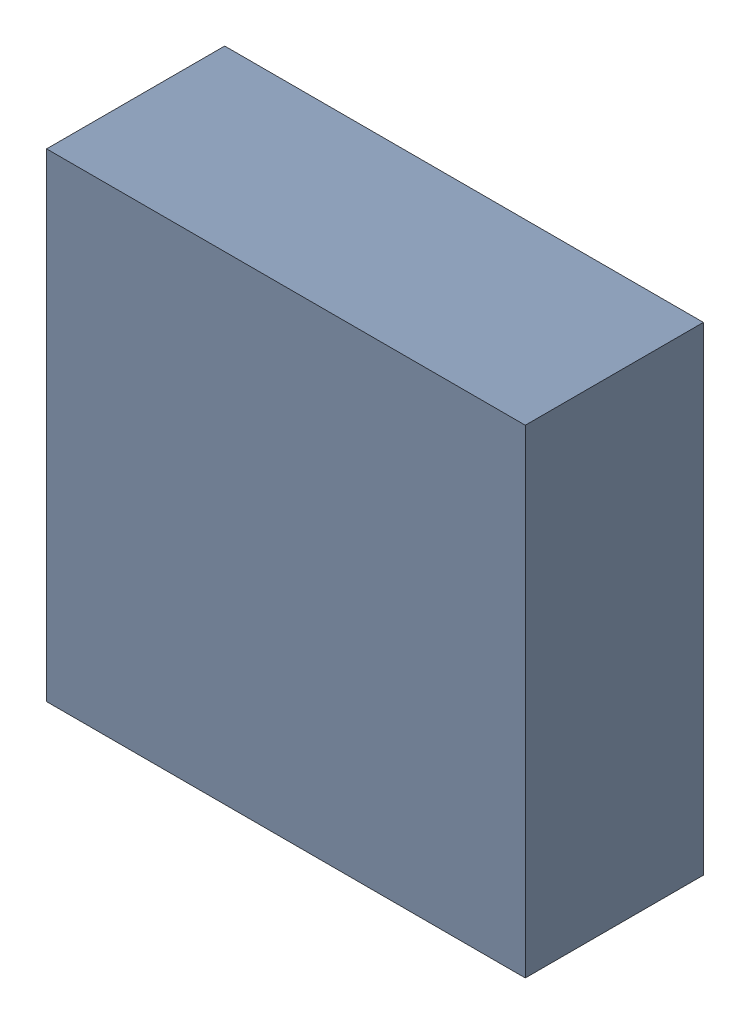
SolidWorks assembly Q6, configuration ﾃﾞﾌｫﾙﾄ. Lengths in mm.
Overall size (2.15 2.15 0.8).
2 component instances, 1 part files, 0 mates.
Components (placement in the parent):
- 689261240-1: 689261240 [ﾃﾞﾌｫﾙﾄ] at (10.4775 14.605 0) size (2.15 2.15 0.8)
  - Extruded_30-1: Extruded_30 [ﾃﾞﾌｫﾙﾄ] at origin size (2.15 2.15 0.8)
